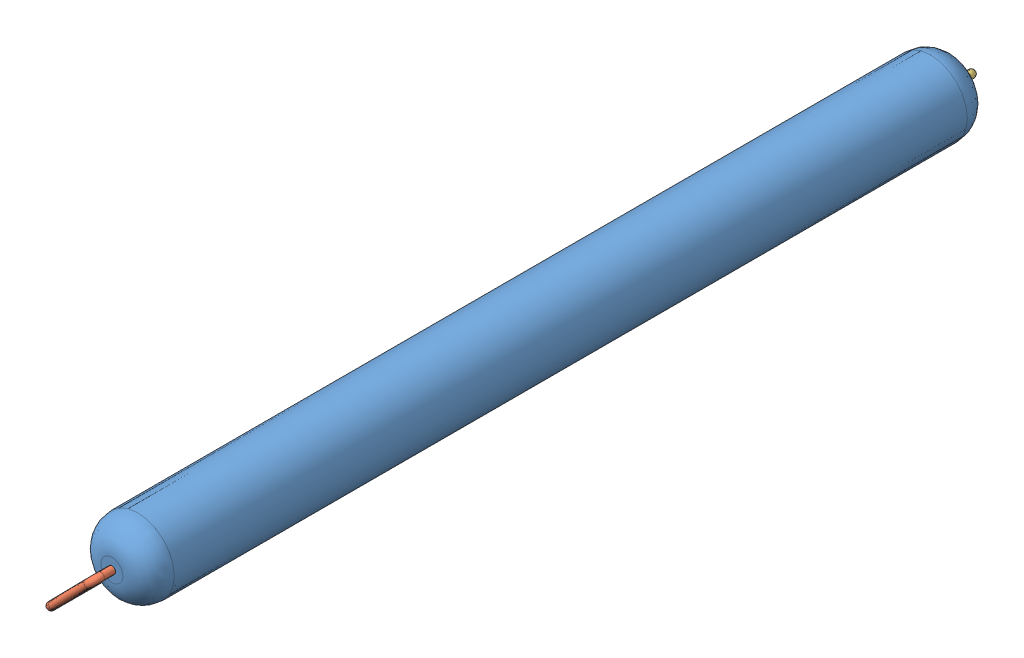
SolidWorks assembly R_J5_J17, configuration Défaut. Lengths in mm.
Overall size (4.54 4.6 24.2).
3 component instances, 3 part files, 5 mates.
Components (placement in the parent):
- R_corps-1: R_corps [Défaut] at (-14.9486 23.7304 -11.5) size (2 2 23)
- R_fil_court-2: R_fil_court [Défaut] at (-14.9486 23.7304 11.5) x (0.700956 0.713204 0) z (0.713204 -0.700956 0) size (4.95 5.14 0.2)
- R_fil_long-4: R_fil_long [Défaut] at (-14.9486 23.7304 -11.5) x (0.700956 0.713204 0) z (-0.713204 0.700956 0) size (5.05 17.25 0.2)
Mates (geometry in assembly coordinates):
- Coaxiale5: concentric aligned: cylinder of R_corps-1 through (-14.9486 23.7304 11.5) axis (0 0 -1) radius 1; cylinder of R_fil_court-2 through (-14.9486 23.7304 11.8) axis (0 0 -1) radius 0.1
- Coïncidente3: coincident anti-aligned: plane of R_corps-1 through (-14.9486 23.7304 11.5) normal (0 0 1); plane of R_fil_court-2 through (-14.9486 23.7304 11.5) normal (0 0 -1)
- Coaxiale7: concentric anti-aligned: cylinder of R_corps-1 through (-14.9486 23.7304 11.5) axis (0 0 -1) radius 1; cylinder of R_fil_long-4 through (-14.9486 23.7304 -11.8) axis (0 0 1) radius 0.1
- Coïncidente5: coincident anti-aligned: plane of R_corps-1 through (-14.9486 23.7304 -11.5) normal (0 0 -1); plane of R_fil_long-4 through (-14.9486 23.7304 -11.5) normal (0 0 1)
- Parallèle1: parallel aligned: plane of R_fil_court-2 through (-18.3448 20.2748 7.0629) normal (-0.700956 -0.713204 0); plane of R_fil_long-4 through (-18.4215 20.1968 5.05) normal (-0.700956 -0.713204 0)
